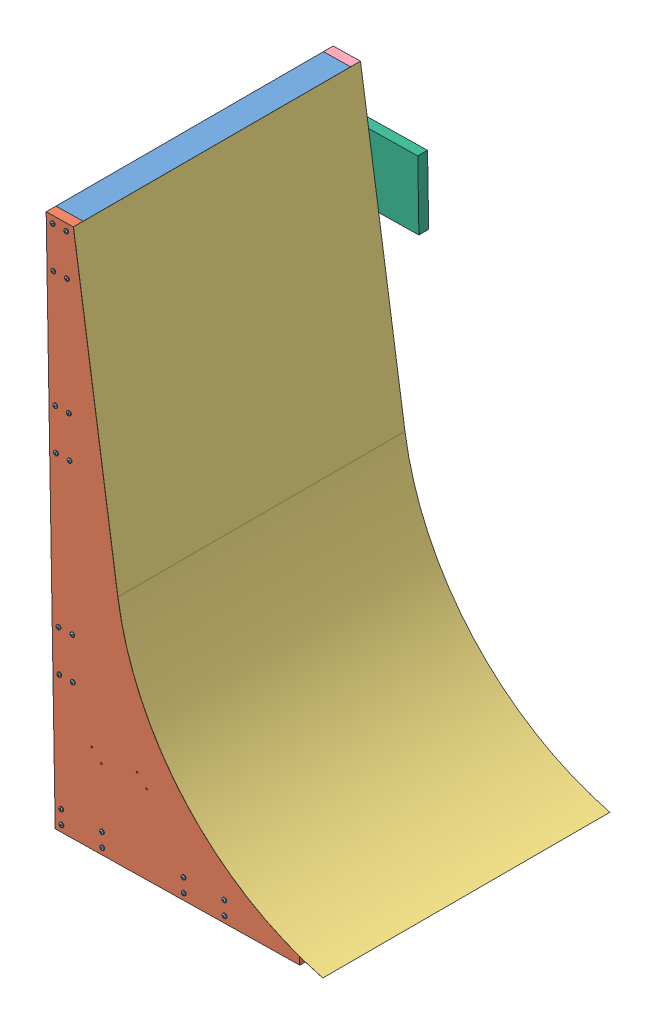
SolidWorks assembly Ramp, configuration Default. Lengths in mm.
Overall size (517.11 999.07 560.24).
51 component instances, 6 part files, 109 mates.
Components (placement in the parent):
- base support-1: base support [Default] at (50.3599 26.2618 18.2563) x (0.999855 0.017038 0) z (0 0 1) size (101.6 50.8 500)
- base support-2: base support [Default] at (278.9267 30.1567 18.2563) x (0.999855 0.017038 0) z (0 0 1) size (101.6 50.8 500)
- base support-3: base support [Default] at (9.3841 940.0963 18.2563) x (0.017038 -0.999855 0) z (0 0 1) size (101.6 50.8 500)
- base support-4: base support [Default] at (14.3609 648.0387 18.2563) x (-0.017038 0.999855 0) z (0 0 1) size (101.6 50.8 500)
- base support-5: base support [Default] at (20.4196 292.4904 18.2563) x (-0.017038 0.999855 0) z (0 0 1) size (101.6 50.8 500)
- Ramp Right Side-2: Ramp Right Side [Default] at (0 0 518.2563) x (0.999855 0.017038 0) z (0 0 1) size (457.2 990.6 18.26)
- ramp top-2: ramp top [Default] at (72.1988 -109.1723 0.0645) x (0.999855 0.017038 0) z (0 0 1) size (449.5 990.69 536.45)
- Left Ramp Side-1: Left Ramp Side [Default] x (0.999855 0.017038 0) z (0 0 1) size (457.2 990.6 18.26)
- Smaller Wood Screw-1: Smaller Wood Screw [93360A255] at (12.049 38.3109 517.4625) x (0 0 -1) z (0.99986 0.016723 0) size (40.83 7.98 7.98)
- Smaller Wood Screw-2: Smaller Wood Screw [93360A255] at (88.238 39.6091 517.4625) x (0 0 -1) z (0.737932 -0.674875 0) size (40.83 7.98 7.98)
- Smaller Wood Screw-3: Smaller Wood Screw [93360A255] at (12.4818 12.9145 517.4625) x (0 0 -1) z (0.728347 -0.685209 0) size (40.83 7.98 7.98)
- Smaller Wood Screw-4: Smaller Wood Screw [93360A255] at (88.6707 14.2128 517.4625) x (0 0 -1) z (0.978218 -0.207583 0) size (40.83 7.98 7.98)
- Smaller Wood Screw-5: Smaller Wood Screw [93360A255] at (240.6158 42.2057 517.4625) x (0 0 -1) z (0.895633 -0.444794 0) size (40.83 7.98 7.98)
- Smaller Wood Screw-6: Smaller Wood Screw [93360A255] at (317.2375 18.1077 517.4625) x (0 0 -1) z (0.927956 -0.37269 0) size (40.83 7.98 7.98)
- Smaller Wood Screw-7: Smaller Wood Screw [93360A255] at (241.0486 16.8094 517.4625) x (0 0 -1) z (0.947454 -0.319891 0) size (40.83 7.98 7.98)
- Smaller Wood Screw-8: Smaller Wood Screw [93360A255] at (316.8048 43.504 517.4625) x (0 0 -1) z (0.916674 -0.399636 0) size (40.83 7.98 7.98)
- Smaller Wood Screw-9: Smaller Wood Screw [93360A255] at (27.7082 610.1607 517.4625) x (0 0 -1) z (-0.434402 -0.900719 0) size (40.83 7.98 7.98)
- Smaller Wood Screw-10: Smaller Wood Screw [93360A255] at (8.3705 254.1795 517.4625) x (0 0 -1) z (0.029195 -0.999574 0) size (40.83 7.98 7.98)
- Smaller Wood Screw-11: Smaller Wood Screw [93360A255] at (2.3119 609.7279 517.4625) x (0 0 -1) z (-0.383207 -0.923662 0) size (40.83 7.98 7.98)
- Smaller Wood Screw-12: Smaller Wood Screw [93360A255] at (33.7669 254.6123 517.4625) x (0 0 -1) z (-0.101676 -0.994818 0) size (40.83 7.98 7.98)
- Smaller Wood Screw-13: Smaller Wood Screw [93360A255] at (32.4686 330.8012 517.0434) x (0 0 -1) z (0.798033 -0.602614 0) size (40.83 7.98 7.98)
- Smaller Wood Screw-14: Smaller Wood Screw [93360A255] at (7.0723 330.3685 517.4625) x (0 0 -1) z (0.916528 -0.39997 0) size (40.83 7.98 7.98)
- Smaller Wood Screw-15: Smaller Wood Screw [93360A255] at (22.7314 902.2183 517.4625) x (0 0 -1) z (0.94297 -0.332878 0) size (40.83 7.98 7.98)
- Smaller Wood Screw-16: Smaller Wood Screw [93360A255] at (21.4332 978.4072 517.4625) x (0 0 -1) z (0.957808 -0.287409 0) size (40.83 7.98 7.98)
- Smaller Wood Screw-17: Smaller Wood Screw [93360A255] at (26.4099 686.3496 517.4625) x (0 0 -1) z (0.9364 -0.350934 0) size (40.83 7.98 7.98)
- Smaller Wood Screw-18: Smaller Wood Screw [93360A255] at (-2.6649 901.7855 517.4625) x (0 0 -1) z (0.929454 -0.368937 0) size (40.83 7.98 7.98)
- Smaller Wood Screw-19: Smaller Wood Screw [93360A255] at (-3.9632 977.9744 517.4625) x (0 0 -1) z (0.716357 -0.697734 0) size (40.83 7.98 7.98)
- Smaller Wood Screw-20: Smaller Wood Screw [93360A255] at (1.0136 685.9168 517.4625) x (0 0 -1) z (0.980156 -0.198228 0) size (40.83 7.98 7.98)
- Smaller Wood Screw-21: Smaller Wood Screw [93360A255] at (21.4332 978.4072 19.05) x (0 0 1) z (-0.976976 0.213347 0) size (40.83 7.98 7.98)
- Smaller Wood Screw-22: Smaller Wood Screw [93360A255] at (-2.6649 901.7855 19.05) x (0 0 1) z (-0.975802 0.218657 0) size (40.83 7.98 7.98)
- Smaller Wood Screw-23: Smaller Wood Screw [93360A255] at (-3.9632 977.9744 19.05) x (0 0 1) z (-0.973932 0.22684 0) size (40.83 7.98 7.98)
- Smaller Wood Screw-24: Smaller Wood Screw [93360A255] at (22.7314 902.2183 19.05) x (0 0 1) z (-0.980702 0.195508 0) size (40.83 7.98 7.98)
- Smaller Wood Screw-25: Smaller Wood Screw [93360A255] at (1.0136 685.9168 19.05) x (0 0 1) z (-0.999462 -0.032793 0) size (40.83 7.98 7.98)
- Smaller Wood Screw-26: Smaller Wood Screw [93360A255] at (2.3119 609.7279 19.05) x (0 0 1) z (-0.993805 0.11114 0) size (40.83 7.98 7.98)
- Smaller Wood Screw-27: Smaller Wood Screw [93360A255] at (26.4099 686.3496 19.05) x (0 0 1) z (-0.996065 0.088627 0) size (40.83 7.98 7.98)
- Smaller Wood Screw-28: Smaller Wood Screw [93360A255] at (27.7082 610.1607 19.05) x (0 0 1) z (-0.990107 0.140311 0) size (40.83 7.98 7.98)
- Smaller Wood Screw-29: Smaller Wood Screw [93360A255] at (32.4686 330.8012 19.05) x (0 0 1) z (-0.984191 0.177108 0) size (40.83 7.98 7.98)
- Smaller Wood Screw-30: Smaller Wood Screw [93360A255] at (8.3705 254.1795 19.05) x (0 0 1) z (-0.989085 0.147348 0) size (40.83 7.98 7.98)
- Smaller Wood Screw-31: Smaller Wood Screw [93360A255] at (7.0723 330.3685 19.05) x (0 0 1) z (-0.990343 0.138636 0) size (40.83 7.98 7.98)
- Smaller Wood Screw-32: Smaller Wood Screw [93360A255] at (33.7669 254.6123 19.05) x (0 0 1) z (-0.990372 0.138429 0) size (40.83 7.98 7.98)
- Smaller Wood Screw-33: Smaller Wood Screw [93360A255] at (12.049 38.3109 19.05) x (0 0 1) z (-0.99641 0.084662 0) size (40.83 7.98 7.98)
- Smaller Wood Screw-34: Smaller Wood Screw [93360A255] at (12.4818 12.9145 19.05) x (0 0 1) z (-0.902798 0.430064 0) size (40.83 7.98 7.98)
- Smaller Wood Screw-35: Smaller Wood Screw [93360A255] at (88.238 39.6091 19.05) x (0 0 1) z (-0.346699 0.937977 0) size (40.83 7.98 7.98)
- Smaller Wood Screw-36: Smaller Wood Screw [93360A255] at (88.6707 14.2128 19.05) x (0 0 1) z (-0.822189 0.569215 0) size (40.83 7.98 7.98)
- Smaller Wood Screw-37: Smaller Wood Screw [93360A255] at (241.0486 16.8094 19.05) x (0 0 1) z (-0.485074 0.874473 0) size (40.83 7.98 7.98)
- Smaller Wood Screw-38: Smaller Wood Screw [93360A255] at (316.8048 43.504 19.05) x (0 0 1) z (0.344552 0.938767 0) size (40.83 7.98 7.98)
- Smaller Wood Screw-39: Smaller Wood Screw [93360A255] at (317.2375 18.1077 19.05) x (0 0 1) z (-0.659807 0.751435 0) size (40.83 7.98 7.98)
- Smaller Wood Screw-40: Smaller Wood Screw [93360A255] at (240.6158 42.2057 19.05) x (0 0 1) z (-0.848855 0.528626 0) size (40.83 7.98 7.98)
- Position Marker-1: Position Marker [Default] at (14.1597 889.3708 -18.2626) x (0.017024 -0.999855 0) z (0 0 1) size (127 127 18.26)
- Smaller Wood Screw-41: Smaller Wood Screw [93360A255] at (39.9884 864.4069 0.7874) x (0 0 1) z (0.509818 0.860282 0) size (40.83 7.98 7.98)
- Smaller Wood Screw-42: Smaller Wood Screw [93360A255] at (51.3172 788.3888 0.7874) x (0 0 1) z (0.395796 -0.918339 0) size (40.83 7.98 7.98)
Mates (geometry in assembly coordinates):
- Distance2: distance = 127 mm: line of base support-1 through (101.5853 1.731 18.2563) axis (-0.017038 0.999855 0); line of base support-2 through (227.7013 54.6875 18.2563) axis (0.017038 -0.999855 0)
- Distance3: distance = 190.5 mm: line of base support-3 through (-15.1467 888.871 18.2563) axis (0.999855 0.017038 0); line of base support-4 through (38.8917 699.2641 18.2563) axis (-0.999855 -0.017038 0)
- Distance4: distance = 190.5 mm: line of base support-5 through (-4.1112 241.265 18.2563) axis (0.999855 0.017038 0); line of base support-1 through (100.7197 52.5237 18.2563) axis (-0.999855 -0.017038 0)
- Coincident18: coincident: plane of base support-1 through (50.3599 26.2618 518.2563) normal (0 0 1); plane of Ramp Right Side-2 through (0 0 518.2563) normal (0 0 -1)
- Coincident19: coincident: line of base support-5 through (-5.8423 342.8502 518.2563) axis (0.017038 -0.999855 0); line of Ramp Right Side-2 through (0 0 518.2563) axis (-0.017038 0.999855 0)
- Coincident20: coincident: line of base support-2 through (228.5668 3.8949 518.2563) axis (0.999855 0.017038 0); line of Ramp Right Side-2 through (0 0 518.2563) axis (0.999855 0.017038 0)
- Coincident28: coincident: line of base support-3 through (33.9149 991.3217 518.2563) axis (0 0 -1); line of ramp top-2 through (33.9149 991.3217 536.5125) axis (0 0 -1)
- Parallel1: parallel: line of Ramp Right Side-2 through (33.9149 991.3217 536.5125) axis (0.147399 -0.989077 0); line of ramp top-2 through (117.2938 433.9561 536.5125) axis (-0.147399 0.989077 0)
- Coincident44: coincident: line of Ramp Right Side-2 through (33.9149 991.3217 536.5125) axis (0.147399 -0.989077 0); line of ramp top-2 through (33.9149 991.3217 536.5125) axis (0.147399 -0.989077 0)
- Coincident48: coincident: plane of base support-1 through (50.3599 26.2618 518.2563) normal (0 0 1); plane of Ramp Right Side-2 through (0 0 518.2563) normal (0 0 -1)
- Coincident50: coincident: line of base support-1 through (-0.8655 50.7926 518.2563) axis (0.017038 -0.999855 0); line of Ramp Right Side-2 through (0 0 518.2563) axis (-0.017038 0.999855 0)
- Coincident51: coincident: line of base support-1 through (0 0 518.2563) axis (0.999855 0.017038 0); line of Ramp Right Side-2 through (0 0 518.2563) axis (0.999855 0.017038 0)
- Coincident58: coincident: plane of base support-1 through (50.3599 26.2618 18.2563) normal (0 0 -1); plane of Left Ramp Side-1 through (0 0 18.2563) normal (0 0 1)
- Parallel2: parallel: line of base support-1 through (0 0 18.2563) axis (0.999855 0.017038 0); line of Left Ramp Side-1 through (0 0 0) axis (0.999855 0.017038 0)
- Coincident60: coincident: line of base support-1 through (-0.8655 50.7926 18.2563) axis (0.017038 -0.999855 0); line of Left Ramp Side-1 through (0 0 18.2563) axis (-0.017038 0.999855 0)
- Coincident61: coincident: line of base support-1 through (0 0 18.2563) axis (0.999855 0.017038 0); line of Left Ramp Side-1 through (0 0 18.2563) axis (0.999855 0.017038 0)
- Coincident62: coincident: plane of base support-3 through (9.3841 940.0963 518.2563) normal (0 0 1); plane of Ramp Right Side-2 through (0 0 518.2563) normal (0 0 -1)
- Coincident63: coincident: plane of base support-4 through (14.3609 648.0387 518.2563) normal (0 0 1); plane of Ramp Right Side-2 through (0 0 518.2563) normal (0 0 -1)
- Coincident64: coincident: line of base support-4 through (-11.9009 698.3986 518.2563) axis (0.017038 -0.999855 0); line of Ramp Right Side-2 through (0 0 518.2563) axis (-0.017038 0.999855 0)
- Coincident65: coincident: line of base support-3 through (33.9149 991.3217 518.2563) axis (-0.999855 -0.017038 0); line of Ramp Right Side-2 through (-16.8777 990.4562 518.2563) axis (0.999855 0.017038 0)
- Coincident66: coincident: point of Left Ramp Side-1; point of assembly
- Concentric3: concentric: cylinder of Ramp Right Side-2 through (12.049 38.3109 518.2563) axis (0 0 1) radius 1.5875; cylinder of Smaller Wood Screw-1 through (12.049 38.3109 536.5125) axis (0 0 1) radius 1.7443
- Coincident67: coincident: plane of Ramp Right Side-2 through (0 0 536.5125) normal (0 0 1); plane of Smaller Wood Screw-1 through (12.0198 40.055 536.5125) normal (0 0 -1)
- Concentric4: concentric: cylinder of Ramp Right Side-2 through (88.238 39.6091 518.2563) axis (0 0 1) radius 1.5875; cylinder of Smaller Wood Screw-2 through (88.238 39.6091 536.5125) axis (0 0 1) radius 1.7443
- Coincident68: coincident: plane of Ramp Right Side-2 through (0 0 536.5125) normal (0 0 1); plane of Smaller Wood Screw-2 through (89.4152 40.8963 536.5125) normal (0 0 -1)
- Concentric5: concentric: cylinder of Ramp Right Side-2 through (12.4818 12.9145 518.2563) axis (0 0 1) radius 1.5875; cylinder of Smaller Wood Screw-3 through (12.4818 12.9145 536.5125) axis (0 0 1) radius 1.7443
- Coincident69: coincident: plane of Ramp Right Side-2 through (0 0 536.5125) normal (0 0 1); plane of Smaller Wood Screw-3 through (13.677 14.185 536.5125) normal (0 0 -1)
- Concentric7: concentric: cylinder of Ramp Right Side-2 through (88.6707 14.2128 518.2563) axis (0 0 1) radius 1.5875; cylinder of Smaller Wood Screw-4 through (88.6707 14.2128 536.5125) axis (0 0 1) radius 1.7443
- Coincident70: coincident: plane of Ramp Right Side-2 through (0 0 536.5125) normal (0 0 1); plane of Smaller Wood Screw-4 through (89.0328 15.9192 536.5125) normal (0 0 -1)
- Concentric8: concentric: cylinder of Ramp Right Side-2 through (240.6158 42.2057 518.2563) axis (0 0 1) radius 1.5875; cylinder of Smaller Wood Screw-5 through (240.6158 42.2057 536.5125) axis (0 0 1) radius 1.7443
- Coincident71: coincident: plane of Ramp Right Side-2 through (0 0 536.5125) normal (0 0 1); circle of Smaller Wood Screw-5
- Concentric9: concentric: cylinder of Ramp Right Side-2 through (241.0486 16.8094 518.2563) axis (0 0 1) radius 1.5875; cylinder of Smaller Wood Screw-7 through (241.0486 16.8094 536.5125) axis (0 0 1) radius 1.7443
- Tangent1: tangent: plane of Ramp Right Side-2 through (0 0 536.5125) normal (0 0 1); torus of Smaller Wood Screw-7
- Concentric10: concentric: cylinder of Ramp Right Side-2 through (316.8048 43.504 518.2563) axis (0 0 1) radius 1.5875; cylinder of Smaller Wood Screw-8 through (316.8048 43.504 536.5125) axis (0 0 1) radius 1.7443
- Coincident72: coincident: plane of Ramp Right Side-2 through (0 0 536.5125) normal (0 0 1); circle of Smaller Wood Screw-8
- Concentric11: concentric: circle of Ramp Right Side-2; cylinder of Smaller Wood Screw-6 through (317.2375 18.1077 536.5125) axis (0 0 1) radius 1.7443
- Coincident73: coincident: plane of Ramp Right Side-2 through (0 0 536.5125) normal (0 0 1); plane of Smaller Wood Screw-6 through (317.8876 19.7264 536.5125) normal (0 0 -1)
- Concentric12: concentric: cylinder of Ramp Right Side-2 through (7.0723 330.3685 518.2563) axis (0 0 1) radius 1.5875; cylinder of Smaller Wood Screw-14 through (7.0723 330.3685 536.5125) axis (0 0 1) radius 1.7443
- Coincident74: coincident: plane of Ramp Right Side-2 through (0 0 536.5125) normal (0 0 1); circle of Smaller Wood Screw-14
- Concentric14: concentric: circle of Ramp Right Side-2; cylinder of Smaller Wood Screw-13 through (32.4686 330.8012 536.0934) axis (0 0 1) radius 1.7443
- Coincident75: coincident: plane of Ramp Right Side-2 through (0 0 536.5125) normal (0 0 1); circle of Smaller Wood Screw-13
- Concentric15: concentric: cylinder of Ramp Right Side-2 through (33.7669 254.6123 518.2563) axis (0 0 1) radius 1.5875; cylinder of Smaller Wood Screw-12 through (33.7669 254.6123 536.5125) axis (0 0 1) radius 1.7443
- Coincident76: coincident: plane of Ramp Right Side-2 through (0 0 536.5125) normal (0 0 1); circle of Smaller Wood Screw-12
- Concentric16: concentric: cylinder of Ramp Right Side-2 through (8.3705 254.1795 518.2563) axis (0 0 1) radius 1.5875; cylinder of Smaller Wood Screw-10 through (8.3705 254.1795 536.5125) axis (0 0 1) radius 1.7443
- Coincident77: coincident: plane of Ramp Right Side-2 through (0 0 536.5125) normal (0 0 1); circle of Smaller Wood Screw-10
- Concentric17: concentric: cylinder of Ramp Right Side-2 through (2.3119 609.7279 518.2563) axis (0 0 1) radius 1.5875; cylinder of Smaller Wood Screw-11 through (2.3119 609.7279 536.5125) axis (0 0 1) radius 1.7443
- Coincident78: coincident: plane of Ramp Right Side-2 through (0 0 536.5125) normal (0 0 1); circle of Smaller Wood Screw-11
- Concentric18: concentric: circle of Ramp Right Side-2; cylinder of Smaller Wood Screw-9 through (27.7082 610.1607 536.5125) axis (0 0 1) radius 1.7443
- Coincident79: coincident: plane of Ramp Right Side-2 through (0 0 536.5125) normal (0 0 1); plane of Smaller Wood Screw-9 through (29.2794 609.4029 536.5125) normal (0 0 -1)
- Concentric19: concentric: cylinder of Ramp Right Side-2 through (1.0136 685.9168 518.2563) axis (0 0 1) radius 1.5875; cylinder of Smaller Wood Screw-20 through (1.0136 685.9168 536.5125) axis (0 0 1) radius 1.7443
- Coincident80: coincident: plane of Ramp Right Side-2 through (0 0 536.5125) normal (0 0 1); circle of Smaller Wood Screw-20
- Concentric20: concentric: cylinder of Ramp Right Side-2 through (26.4099 686.3496 518.2563) axis (0 0 1) radius 1.5875; cylinder of Smaller Wood Screw-17 through (26.4099 686.3496 536.5125) axis (0 0 1) radius 1.7443
- Coincident81: coincident: plane of Ramp Right Side-2 through (0 0 536.5125) normal (0 0 1); plane of Smaller Wood Screw-17 through (27.0221 687.983 536.5125) normal (0 0 -1)
- Concentric21: concentric: cylinder of Ramp Right Side-2 through (-2.6649 901.7855 518.2563) axis (0 0 1) radius 1.5875; cylinder of Smaller Wood Screw-18 through (-2.6649 901.7855 536.5125) axis (0 0 1) radius 1.7443
- Coincident82: coincident: plane of Ramp Right Side-2 through (0 0 536.5125) normal (0 0 1); plane of Smaller Wood Screw-18 through (-2.0213 903.4068 536.5125) normal (0 0 -1)
- Concentric22: concentric: circle of Ramp Right Side-2; cylinder of Smaller Wood Screw-15 through (22.7314 902.2183 536.5125) axis (0 0 1) radius 1.7443
- Coincident84: coincident: plane of Ramp Right Side-2 through (0 0 536.5125) normal (0 0 1); plane of Smaller Wood Screw-15 through (23.3121 903.8631 536.5125) normal (0 0 -1)
- Concentric24: concentric: cylinder of Ramp Right Side-2 through (21.4332 978.4072 518.2563) axis (0 0 1) radius 1.5875; cylinder of Smaller Wood Screw-16 through (21.4332 978.4072 536.5125) axis (0 0 1) radius 1.7443
- Coincident85: coincident: plane of Ramp Right Side-2 through (0 0 536.5125) normal (0 0 1); plane of Smaller Wood Screw-16 through (21.9345 980.0779 536.5125) normal (0 0 -1)
- Concentric25: concentric: cylinder of Ramp Right Side-2 through (-3.9632 977.9744 518.2563) axis (0 0 1) radius 1.5875; cylinder of Smaller Wood Screw-19 through (-3.9632 977.9744 536.5125) axis (0 0 1) radius 1.7443
- Coincident86: coincident: plane of Ramp Right Side-2 through (0 0 536.5125) normal (0 0 1); plane of Smaller Wood Screw-19 through (-2.7461 979.224 536.5125) normal (0 0 -1)
- Concentric26: concentric: cylinder of Left Ramp Side-1 through (21.4332 978.4072 0) axis (0 0 1) radius 1.5875; cylinder of Smaller Wood Screw-21 through (21.4332 978.4072 0) axis (0 0 -1) radius 1.7443
- Coincident87: coincident: plane of Left Ramp Side-1 through (0 0 0) normal (0 0 -1); plane of Smaller Wood Screw-21 through (21.8053 980.1114 0) normal (0 0 1)
- Concentric27: concentric: cylinder of Left Ramp Side-1 through (-3.9632 977.9744 0) axis (0 0 1) radius 1.5875; cylinder of Smaller Wood Screw-23 through (-3.9632 977.9744 0) axis (0 0 -1) radius 1.7443
- Coincident88: coincident: plane of Left Ramp Side-1 through (0 0 0) normal (0 0 -1); plane of Smaller Wood Screw-23 through (-3.5675 979.6733 0) normal (0 0 1)
- Concentric28: concentric: cylinder of Left Ramp Side-1 through (22.7314 902.2183 0) axis (0 0 1) radius 1.5875; cylinder of Smaller Wood Screw-24 through (22.7314 902.2183 0) axis (0 0 -1) radius 1.7443
- Coincident89: coincident: plane of Left Ramp Side-1 through (0 0 0) normal (0 0 -1); plane of Smaller Wood Screw-24 through (23.0725 903.9289 0) normal (0 0 1)
- Concentric29: concentric: cylinder of Left Ramp Side-1 through (-2.6649 901.7855 0) axis (0 0 1) radius 1.5875; cylinder of Smaller Wood Screw-22 through (-2.6649 901.7855 0) axis (0 0 -1) radius 1.7443
- Coincident90: coincident: plane of Left Ramp Side-1 through (0 0 0) normal (0 0 -1); plane of Smaller Wood Screw-22 through (-2.2835 903.4876 0) normal (0 0 1)
- Concentric30: concentric: cylinder of Left Ramp Side-1 through (1.0136 685.9168 0) axis (0 0 1) radius 1.5875; cylinder of Smaller Wood Screw-25 through (1.0136 685.9168 0) axis (0 0 -1) radius 1.7443
- Coincident91: coincident: plane of Left Ramp Side-1 through (0 0 0) normal (0 0 -1); circle of Smaller Wood Screw-25
- Concentric31: concentric: cylinder of Left Ramp Side-1 through (26.4099 686.3496 0) axis (0 0 1) radius 1.5875; cylinder of Smaller Wood Screw-27 through (26.4099 686.3496 0) axis (0 0 -1) radius 1.7443
- Coincident92: coincident: plane of Left Ramp Side-1 through (0 0 0) normal (0 0 -1); circle of Smaller Wood Screw-27
- Concentric32: concentric: cylinder of Left Ramp Side-1 through (2.3119 609.7279 0) axis (0 0 1) radius 1.5875; cylinder of Smaller Wood Screw-26 through (2.3119 609.7279 0) axis (0 0 -1) radius 1.7443
- Coincident93: coincident: plane of Left Ramp Side-1 through (0 0 0) normal (0 0 -1); circle of Smaller Wood Screw-26
- Concentric33: concentric: cylinder of Left Ramp Side-1 through (27.7082 610.1607 0) axis (0 0 1) radius 1.5875; cylinder of Smaller Wood Screw-28 through (27.7082 610.1607 0) axis (0 0 -1) radius 1.7443
- Coincident94: coincident: plane of Left Ramp Side-1 through (0 0 0) normal (0 0 -1); plane of Smaller Wood Screw-28 through (27.9529 611.8877 0) normal (0 0 1)
- Concentric34: concentric: cylinder of Left Ramp Side-1 through (32.4686 330.8012 0) axis (0 0 1) radius 1.5875; cylinder of Smaller Wood Screw-29 through (32.4686 330.8012 0) axis (0 0 -1) radius 1.7443
- Concentric35: concentric: cylinder of Left Ramp Side-1 through (7.0723 330.3685 0) axis (0 0 1) radius 1.5875; cylinder of Smaller Wood Screw-31 through (7.0723 330.3685 0) axis (0 0 -1) radius 1.7443
- Coincident95: coincident: plane of Left Ramp Side-1 through (0 0 0) normal (0 0 -1); circle of Smaller Wood Screw-29
- Coincident96: coincident: plane of Left Ramp Side-1 through (0 0 0) normal (0 0 -1); plane of Smaller Wood Screw-31 through (7.3141 332.096 0) normal (0 0 1)
- Concentric36: concentric: cylinder of Left Ramp Side-1 through (33.7669 254.6123 0) axis (0 0 1) radius 1.5875; cylinder of Smaller Wood Screw-32 through (33.7669 254.6123 0) axis (0 0 -1) radius 1.7443
- Concentric37: concentric: cylinder of Left Ramp Side-1 through (8.3705 254.1795 0) axis (0 0 1) radius 1.5875; cylinder of Smaller Wood Screw-30 through (8.3705 254.1795 0) axis (0 0 -1) radius 1.7443
- Coincident98: coincident: plane of Left Ramp Side-1 through (0 0 0) normal (0 0 -1); plane of Smaller Wood Screw-30 through (8.6276 255.9048 0) normal (0 0 1)
- Coincident99: coincident: plane of Left Ramp Side-1 through (0 0 0) normal (0 0 -1); plane of Smaller Wood Screw-32 through (34.0083 256.3398 0) normal (0 0 1)
- Concentric38: concentric: cylinder of Left Ramp Side-1 through (12.049 38.3109 0) axis (0 0 1) radius 1.5875; cylinder of Smaller Wood Screw-33 through (12.049 38.3109 0) axis (0 0 -1) radius 1.7443
- Coincident100: coincident: plane of Left Ramp Side-1 through (0 0 0) normal (0 0 -1); circle of Smaller Wood Screw-33
- Concentric39: concentric: cylinder of Left Ramp Side-1 through (12.4818 12.9145 0) axis (0 0 1) radius 1.5875; cylinder of Smaller Wood Screw-34 through (12.4818 12.9145 0) axis (0 0 -1) radius 1.7443
- Coincident101: coincident: plane of Left Ramp Side-1 through (0 0 0) normal (0 0 -1); circle of Smaller Wood Screw-34
- Concentric40: concentric: cylinder of Left Ramp Side-1 through (88.6707 14.2128 0) axis (0 0 1) radius 1.5875; cylinder of Smaller Wood Screw-36 through (88.6707 14.2128 0) axis (0 0 -1) radius 1.7443
- Tangent2: tangent: plane of Left Ramp Side-1 through (0 0 0) normal (0 0 -1); torus of Smaller Wood Screw-36
- Concentric41: concentric: cylinder of Left Ramp Side-1 through (88.238 39.6091 0) axis (0 0 1) radius 1.5875; cylinder of Smaller Wood Screw-35 through (88.238 39.6091 0) axis (0 0 -1) radius 1.7443
- Tangent3: tangent: plane of Left Ramp Side-1 through (0 0 0) normal (0 0 -1); torus of Smaller Wood Screw-35
- Concentric42: concentric: circle of Left Ramp Side-1; cylinder of Smaller Wood Screw-40 through (240.6158 42.2057 0) axis (0 0 -1) radius 1.7443
- Coincident106: coincident: plane of Left Ramp Side-1 through (0 0 0) normal (0 0 -1); plane of Smaller Wood Screw-40 through (241.5379 43.6864 0) normal (0 0 1)
- Concentric43: concentric: circle of Left Ramp Side-1; cylinder of Smaller Wood Screw-37 through (241.0486 16.8094 0) axis (0 0 -1) radius 1.7443
- Coincident107: coincident: plane of Left Ramp Side-1 through (0 0 0) normal (0 0 -1); plane of Smaller Wood Screw-37 through (242.574 17.6555 0) normal (0 0 1)
- Concentric44: concentric: cylinder of Left Ramp Side-1 through (316.8048 43.504 0) axis (0 0 1) radius 1.5875; cylinder of Smaller Wood Screw-38 through (316.8048 43.504 0) axis (0 0 -1) radius 1.7443
- Coincident108: coincident: plane of Left Ramp Side-1 through (0 0 0) normal (0 0 -1); plane of Smaller Wood Screw-38 through (318.4423 42.903 0) normal (0 0 1)
- Concentric45: concentric: cylinder of Left Ramp Side-1 through (317.2375 18.1077 0) axis (0 0 1) radius 1.5875; cylinder of Smaller Wood Screw-39 through (317.2375 18.1077 0) axis (0 0 -1) radius 1.7443
- Coincident109: coincident: plane of Left Ramp Side-1 through (0 0 0) normal (0 0 -1); plane of Smaller Wood Screw-39 through (318.5483 19.2586 0) normal (0 0 1)
- Coincident122: coincident: plane of Left Ramp Side-1 through (0 0 0) normal (0 0 -1); plane of Position Marker-1 through (14.1597 889.3708 0) normal (0 0 1)
- Coincident124: coincident: circle of Left Ramp Side-1; circle of Position Marker-1
- Coincident126: coincident: circle of Left Ramp Side-1; circle of Position Marker-1
- Concentric46: concentric: cylinder of Position Marker-1 through (51.3172 788.3888 0) axis (0 0 -1) radius 1.5875; cylinder of Smaller Wood Screw-42 through (51.3172 788.3888 -18.2626) axis (0 0 -1) radius 1.7443
- Concentric47: concentric: cylinder of Position Marker-1 through (39.9884 864.4069 0) axis (0 0 -1) radius 1.5875; cylinder of Smaller Wood Screw-41 through (39.9884 864.4069 -18.2626) axis (0 0 -1) radius 1.7443
- Coincident129: coincident: plane of Position Marker-1 through (14.1597 889.3708 -18.2626) normal (0 0 -1); plane of Smaller Wood Screw-41 through (41.4891 863.5176 -18.2626) normal (0 0 1)
- Tangent4: tangent: plane of Position Marker-1 through (14.1597 889.3708 -18.2626) normal (0 0 -1); torus of Smaller Wood Screw-42
- Parallel5: parallel: plane of Ramp Right Side-2 through (0 0 536.5125) normal (0.017038 -0.999855 0); plane of Left Ramp Side-1 through (0 0 18.2563) normal (0.017038 -0.999855 0)
